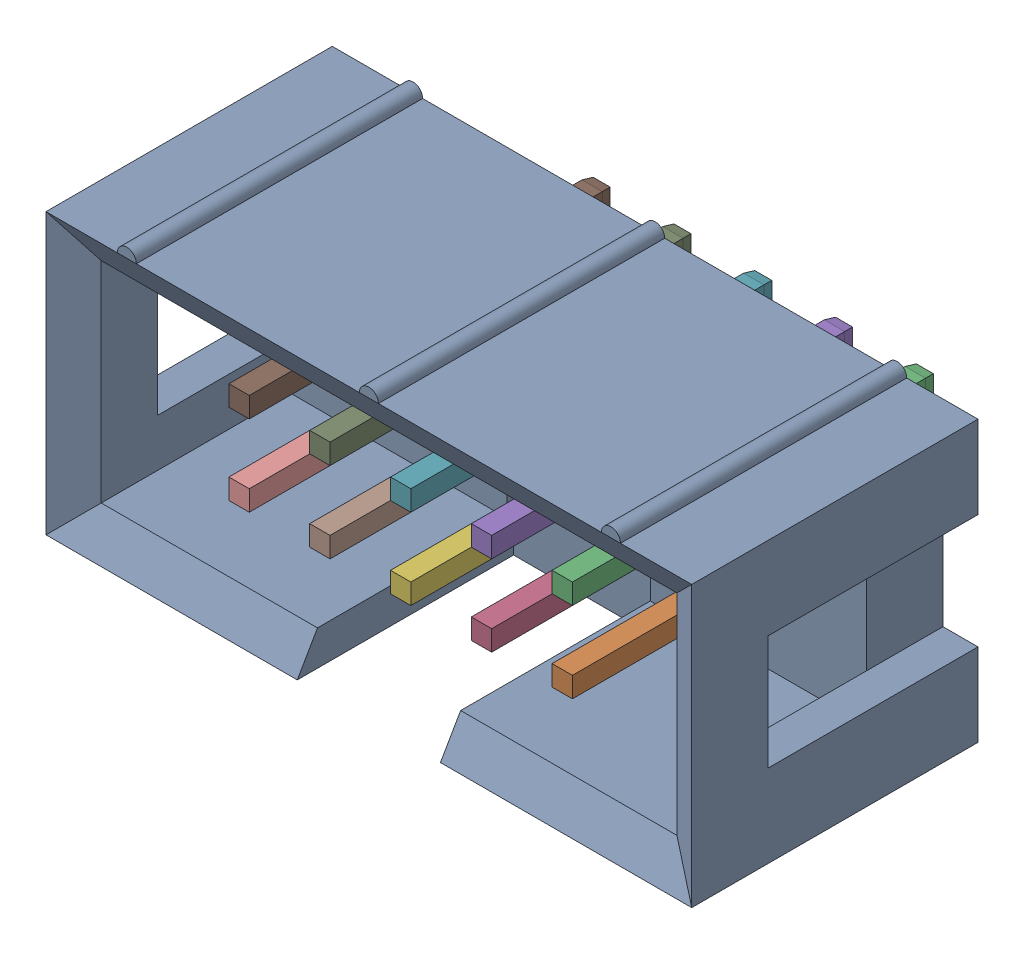
SolidWorks assembly User Library-IDC-10M, configuration 默认. Lengths in mm.
Overall size (20.3 9.1 12.4).
11 component instances, 2 part files, 0 mates.
Components (placement in the parent):
- IDC-10M_Body___ _________-1: IDC-10M_Body___ _________ [默认] at origin size (20.3 9.1 9.3)
- IDC_pin___ _________-1: IDC_pin___ _________ [默认] at (5.08 -1.27 -3.1) size (0.64 0.64 11.4)
- IDC_pin___ _________-2: IDC_pin___ _________ [默认] at (5.08 1.27 -3.1) size (0.64 0.64 11.4)
- IDC_pin___ _________-3: IDC_pin___ _________ [默认] at (2.54 -1.27 -3.1) size (0.64 0.64 11.4)
- IDC_pin___ _________-4: IDC_pin___ _________ [默认] at (2.54 1.27 -3.1) size (0.64 0.64 11.4)
- IDC_pin___ _________-5: IDC_pin___ _________ [默认] at (0 -1.27 -3.1) size (0.64 0.64 11.4)
- IDC_pin___ _________-6: IDC_pin___ _________ [默认] at (0 1.27 -3.1) size (0.64 0.64 11.4)
- IDC_pin___ _________-7: IDC_pin___ _________ [默认] at (-2.54 -1.27 -3.1) size (0.64 0.64 11.4)
- IDC_pin___ _________-8: IDC_pin___ _________ [默认] at (-2.54 1.27 -3.1) size (0.64 0.64 11.4)
- IDC_pin___ _________-9: IDC_pin___ _________ [默认] at (-5.08 -1.27 -3.1) size (0.64 0.64 11.4)
- IDC_pin___ _________-10: IDC_pin___ _________ [默认] at (-5.08 1.27 -3.1) size (0.64 0.64 11.4)
